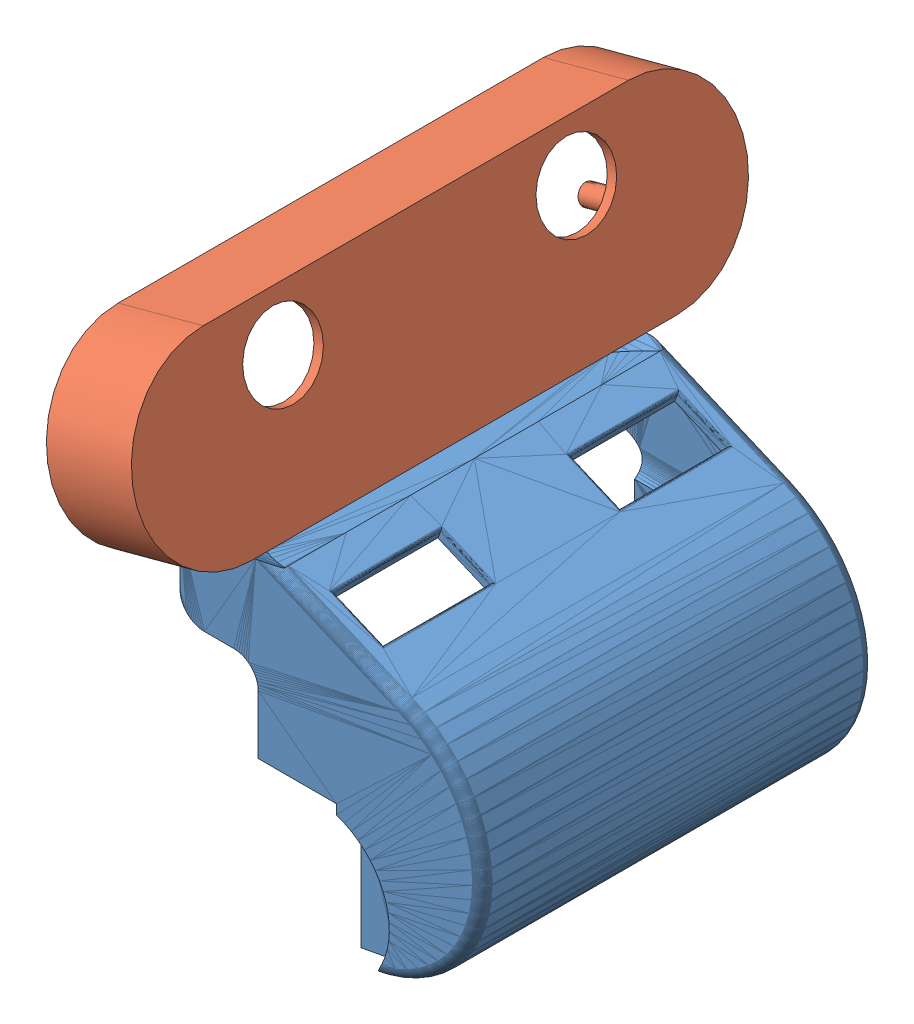
SolidWorks assembly Assem1, configuration Default. Lengths in mm.
Overall size (70.72 102.8 125).
2 component instances, 2 part files, 2 mates.
Components (placement in the parent):
- cover-rs-1: cover-rs [Default] at (40.0152 11.5457 86.7129) x (1 0 0) z (0 1 0) size (61.84 80 63.28)
- cam_cov-1: cam_cov [Default] at (19.5016 95.4801 86.9629) x (0 0 -1) z (0.965915 0.258859 0) size (125 46 18)
Mates (geometry in assembly coordinates):
- Coincident1: coincident anti-aligned: plane of cover-rs-1 through (34.1354 9.97 86.7129) normal (-0.965915 -0.258859 0); plane of cam_cov-1 through (18.7635 67.3295 75.4629) normal (0.965915 0.258859 0)
- Width1: width aligned: plane of cover-rs-1 through (39.4513 17.9873 50.0414) normal (0.015141 -0.172987 0.984808); plane of cam_cov-1 through (40.018 11.5136 86.5302) normal (0.015141 -0.172987 -0.984808); plane of cover-rs-1 through (12.0986 65.5434 59.9629) normal (0 0 -1); plane of cam_cov-1 through (12.0986 65.5434 75.4629) normal (0 0 1)
